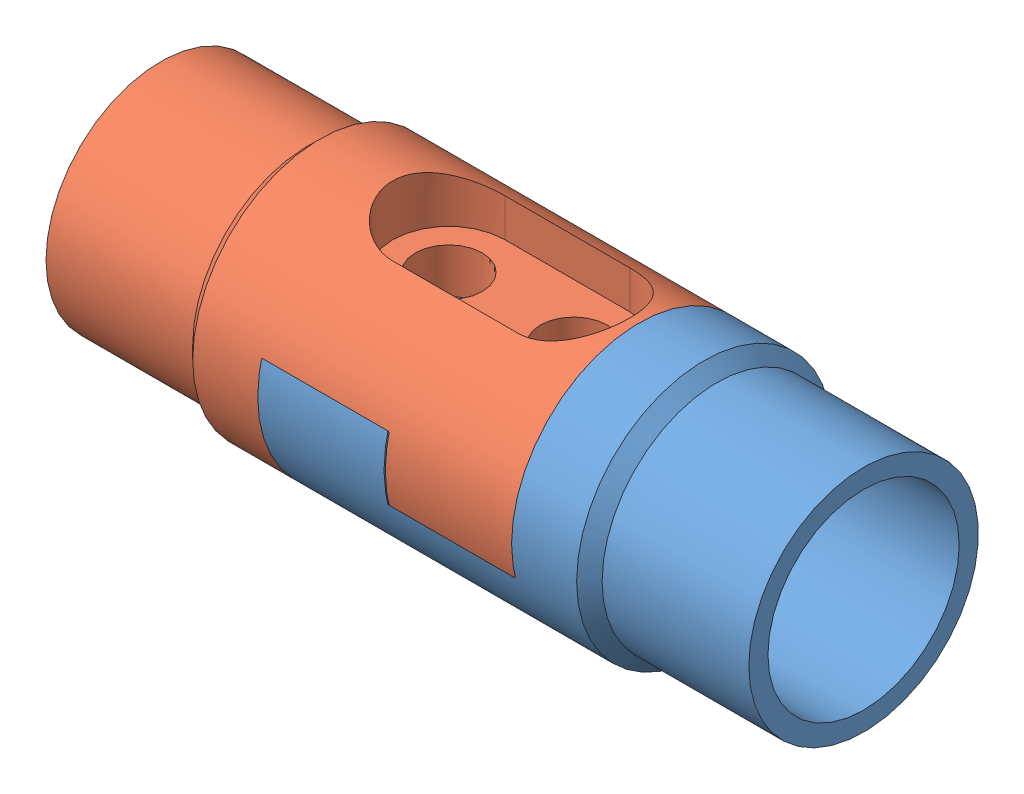
SolidWorks assembly Assemblage tube interloocking , configuration Défaut. Lengths in mm.
Overall size (110.2 40 42.6).
2 component instances, 2 part files, 3 mates.
Components (placement in the parent):
- Tube interlocking Dernière version -2: Tube interlocking Dernière version  [Défaut] at (86.9081 5.9422 75) size (75 40 40)
- Tube interlocking 2  Dernière version -3: Tube interlocking 2  Dernière version  [Défaut] at (-66.7331 -15.0656 75) x (-1 0 0) z (0 0 1) size (75 40 42.6)
Mates (geometry in assembly coordinates):
- Verrouiller1: lock: unknown of Tube interlocking Dernière version -2
- Distance1: distance = 0 mm: line of Tube interlocking 2  Dernière version -3 through (10.3875 -9.5617 94.3649) axis (1 0 0); line of Tube interlocking Dernière version -2 through (29.7875 -9.5617 94.3649) axis (-1 0 0)
- Coïncidente1: coincident aligned: circle of Tube interlocking Dernière version -2; circle of Tube interlocking 2  Dernière version -3
